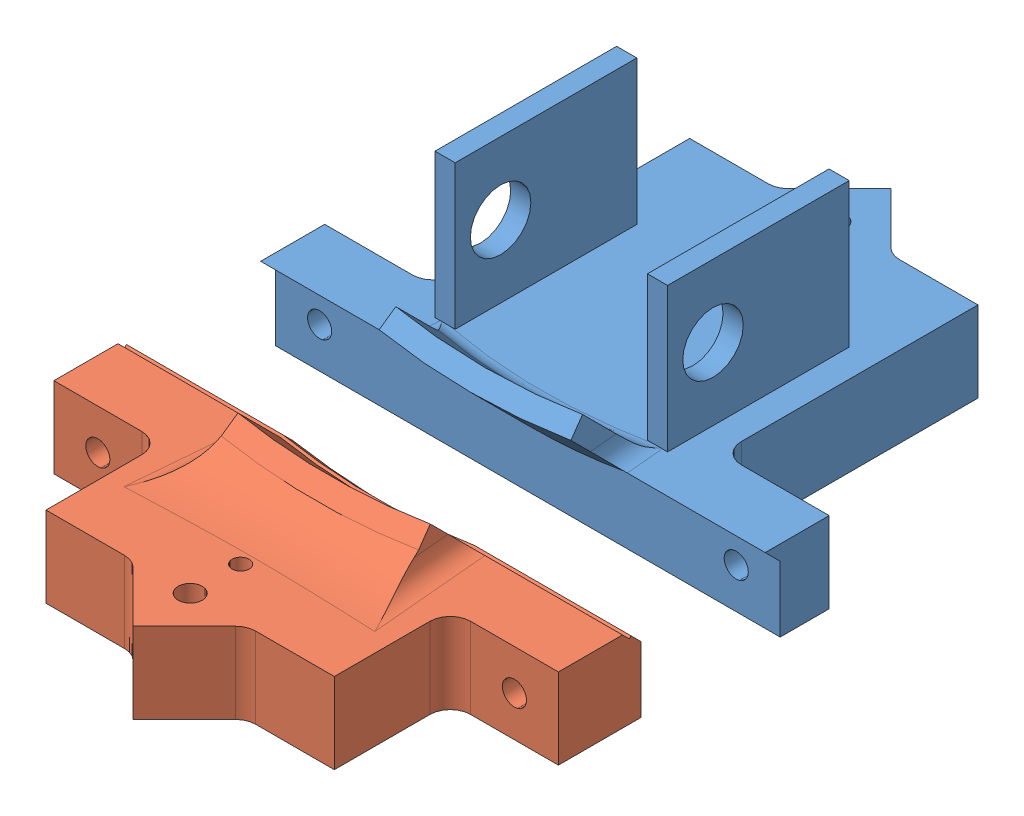
SolidWorks assembly TwoPartMountAssembly, configuration Default. Lengths in mm.
Overall size (50 22.29 75.1).
2 component instances, 2 part files, 3 mates.
Components (placement in the parent):
- TwoPartMountA-1: TwoPartMountA [Default] at origin size (50 22.29 41.64)
- TwoPartMountB-1: TwoPartMountB [Default] at (0 0 13.7893) size (50 11.58 25.34)
Mates (geometry in assembly coordinates):
- Coincident1: coincident aligned: plane of Two part mount B-1 through (0 0 13.7893) normal (1 0 0)
- Coincident2: coincident aligned: plane of Two part mount B-1 through (0 0 13.7893) normal (0 1 0)
- LimitDistance1: limit distance = 13.7893 mm anti-aligned: plane of Two part mount A-1 through (-25 9 5.3162) normal (0 0 1); plane of Two part mount B-1 through (-25 9 19.1055) normal (0 0 -1)
